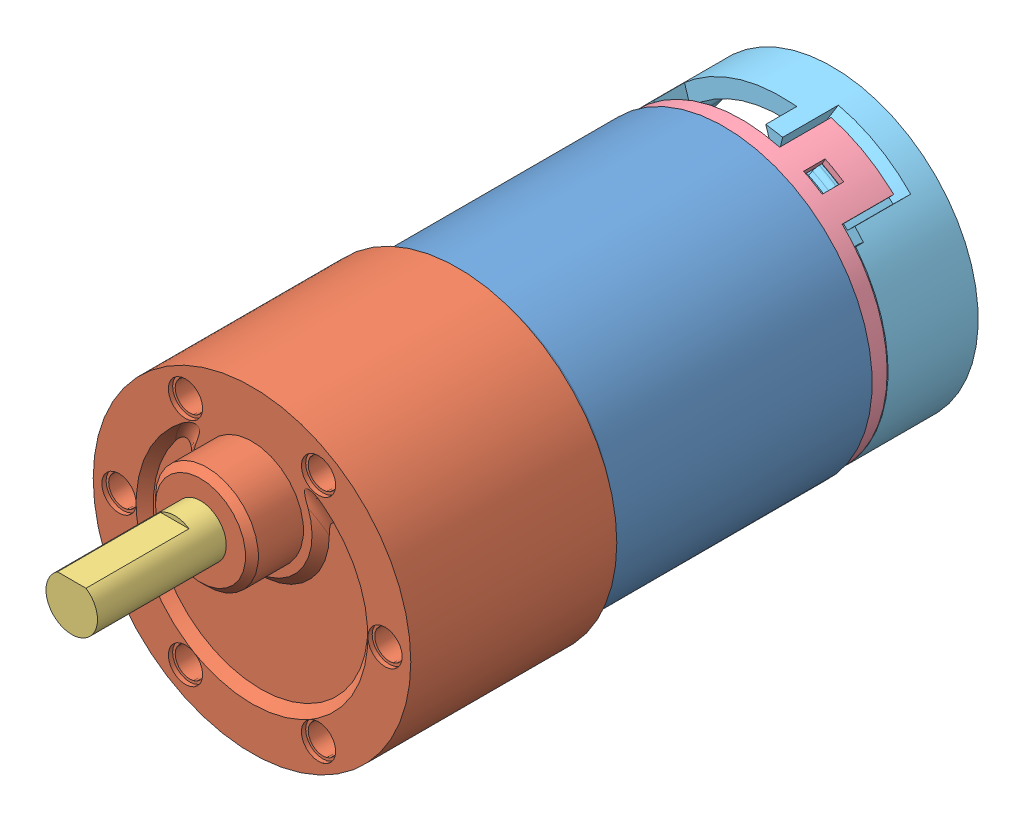
SolidWorks assembly Motor_w_Encoder_Cap_F_rev1, configuration Default. Lengths in mm.
Overall size (42.65 42.65 88.6).
5 component instances, 5 part files, 13 mates.
Components (placement in the parent):
- Motor_rev0-1: Motor_rev0 [Default] at (12.0471 18.5029 10.1025) size (34.5 34.5 31)
- Gearbox_rev0-1: Gearbox_rev0 [Default] at (12.0471 18.5029 41.1025) size (37 37 30)
- Shaft_rev0-1: Shaft_rev0 [Default] at (12.0471 25.5029 65.1025) size (6 6 21)
- Back_Motor_Cover_rev0-1: Back_Motor_Cover_rev0 [Default] at (12.0471 18.5029 10.1025) x (0.953717 0.300706 0) z (0 0 -1) size (34 34 8)
- Encoder_Cap_F_rev0-2-2: Encoder_Cap_F_rev0-2 [Default] at (12.0471 18.5029 -2.4975) x (-0.953717 -0.300706 0) z (0 0 1) size (34 34 10.5)
Mates (geometry in assembly coordinates):
- Coincident1: coincident anti-aligned: plane of Motor_rev0-1 through (12.0471 18.5029 41.1025) normal (0 0 1); plane of Gearbox_rev0-1 through (12.0471 18.5029 41.1025) normal (0 0 -1)
- Concentric1: concentric aligned: cylinder of Motor_rev0-1 through (12.0471 18.5029 41.1025) axis (0 0 -1) radius 17.25; cylinder of Gearbox_rev0-1 through (12.0471 18.5029 65.1025) axis (0 0 -1) radius 18.5
- Lock1: lock: unknown of Motor_rev0-1; unknown of Gearbox_rev0-1
- Hinge1: hinge anti-aligned: cylinder of Gearbox_rev0-1 through (12.0471 25.5029 71.1025) axis (0 0 -1) radius 3; cylinder of Shaft_rev0-1 through (12.0471 25.5029 86.1025) axis (0 0 -1) radius 3; plane of Gearbox_rev0-1 through (12.0471 18.5029 65.1025) normal (0 0 1); plane of Shaft_rev0-1 through (12.0471 25.5029 65.1025) normal (0 0 -1)
- Coincident2: coincident anti-aligned: plane of Motor_rev0-1 through (12.0471 18.5029 10.1025) normal (0 0 -1); plane of Back_Motor_Cover_rev0-1 through (12.0471 18.5029 10.1025) normal (0 0 1)
- Concentric2: concentric anti-aligned: cylinder of Motor_rev0-1 through (12.0471 18.5029 41.1025) axis (0 0 -1) radius 17.25; cylinder of Back_Motor_Cover_rev0-1 through (12.0471 18.5029 8.1025) axis (0 0 1) radius 17
- Coincident3: coincident aligned: plane of Shaft_rev0-1 through (12.0471 25.5029 65.1025) normal (1 0 0); plane of Back_Motor_Cover_rev0-1 through (12.0471 18.5029 10.1025) normal (1 0 0)
- Coincident4: coincident anti-aligned: plane of Back_Motor_Cover_rev0-1 through (12.0471 18.5029 7.1025) normal (0 0 -1); plane of Encoder_Cap_F_rev0-1 through (12.0471 18.5029 7.1025) normal (0 0 1)
- Concentric3: concentric aligned: cylinder of Back_Motor_Cover_rev0-1 through (12.0471 18.5029 2.1025) axis (0 0 1) radius 16.25; cylinder of Encoder_Cap_F_rev0-1 through (12.0471 18.5029 0.5025) axis (0 0 1) radius 15.8
- Coincident5: coincident aligned: plane of Back_Motor_Cover_rev0-1 through (12.0471 18.5029 10.1025) normal (0.953717 0.300706 0); plane of Encoder_Cap_F_rev0-1 through (12.0471 18.5029 -2.7475) normal (0.953717 0.300706 0)
- Concentric4: concentric anti-aligned: cylinder of Back_Motor_Cover_rev0-1 through (12.0471 18.5029 8.1025) axis (0 0 1) radius 17; cylinder of Encoder_Cap_F_rev0-2-2 through (12.0471 18.5029 8.0025) axis (0 0 -1) radius 17
- Coincident6: coincident anti-aligned: plane of Back_Motor_Cover_rev0-1 through (12.0471 18.5029 7.1025) normal (0 0 -1); plane of Encoder_Cap_F_rev0-2-2 through (12.0471 18.5029 7.1025) normal (0 0 1)
- Coincident7: coincident aligned: plane of Back_Motor_Cover_rev0-1 through (12.0471 18.5029 10.1025) normal (0.953717 0.300706 0); plane of Encoder_Cap_F_rev0-2-2 through (12.0471 18.5029 -2.4975) normal (0.953717 0.300706 0)
